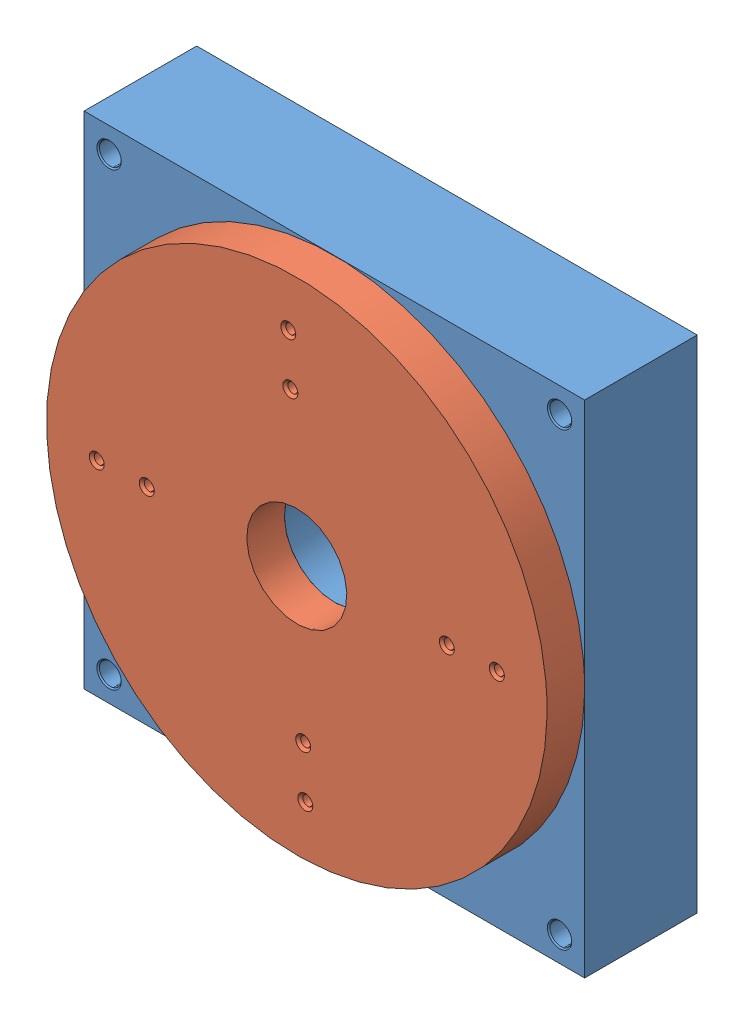
SolidWorks assembly 10in_stage, configuration Default. Lengths in mm.
Overall size (264.6 264.6 76.2).
2 component instances, 2 part files, 2 mates.
Components (placement in the parent):
- 10in_stage_base-1: 10in_stage_base [Default] at (-41.472 -7.0952 55.2796) size (254 254 57.15)
- 10in_stage_plate-1: 10in_stage_plate [Default] at (-41.472 -7.0952 55.2796) x (0.999091 0.042638 0) z (0 0 1) size (254 254 19.05)
Mates (geometry in assembly coordinates):
- Concentric1: concentric anti-aligned: cylinder of 10in_stage_base-1 through (-41.472 -7.0952 -1.8704) axis (0 0 1) radius 25.4; cylinder of 10in_stage_plate-1 through (-41.472 -7.0952 74.3296) axis (0 0 -1) radius 25.4
- Coincident1: coincident anti-aligned: plane of 10in_stage_base-1 through (-41.472 -7.0952 55.2796) normal (0 0 1); plane of 10in_stage_plate-1 through (-41.472 -7.0952 55.2796) normal (0 0 -1)
